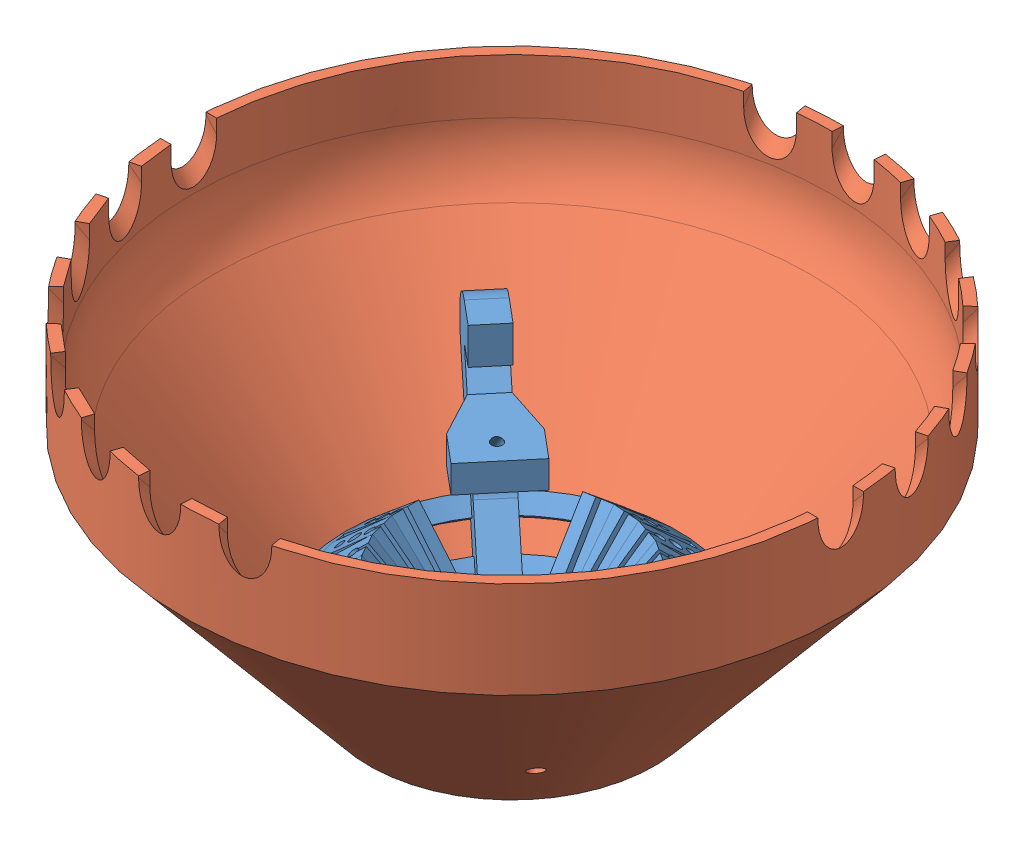
SolidWorks assembly DriveAndConeAssembly, configuration Default. Lengths in mm.
Overall size (101.86 40.61 101.86).
2 component instances, 2 part files, 2 mates.
Components (placement in the parent):
- drive_circle_16_mcube-1: drive_circle_16_mcube [Default] at (11.0772 17.9945 56.5499) size (42.84 26.14 36.74)
- Drive16_Cone-1: Drive16_Cone [Default] at (11.0772 23.4535 56.5499) x (0.766044 0 0.642788) z (0.642788 0 -0.766044) size (72.3 35.15 72.3)
Mates (geometry in assembly coordinates):
- Concentric4: concentric anti-aligned: circle of drive_circle_16_mcube-1; circle of Drive16_Cone-1
- Concentric5: concentric aligned: circle of drive_circle_16_mcube-1; circle of Drive16_Cone-1
